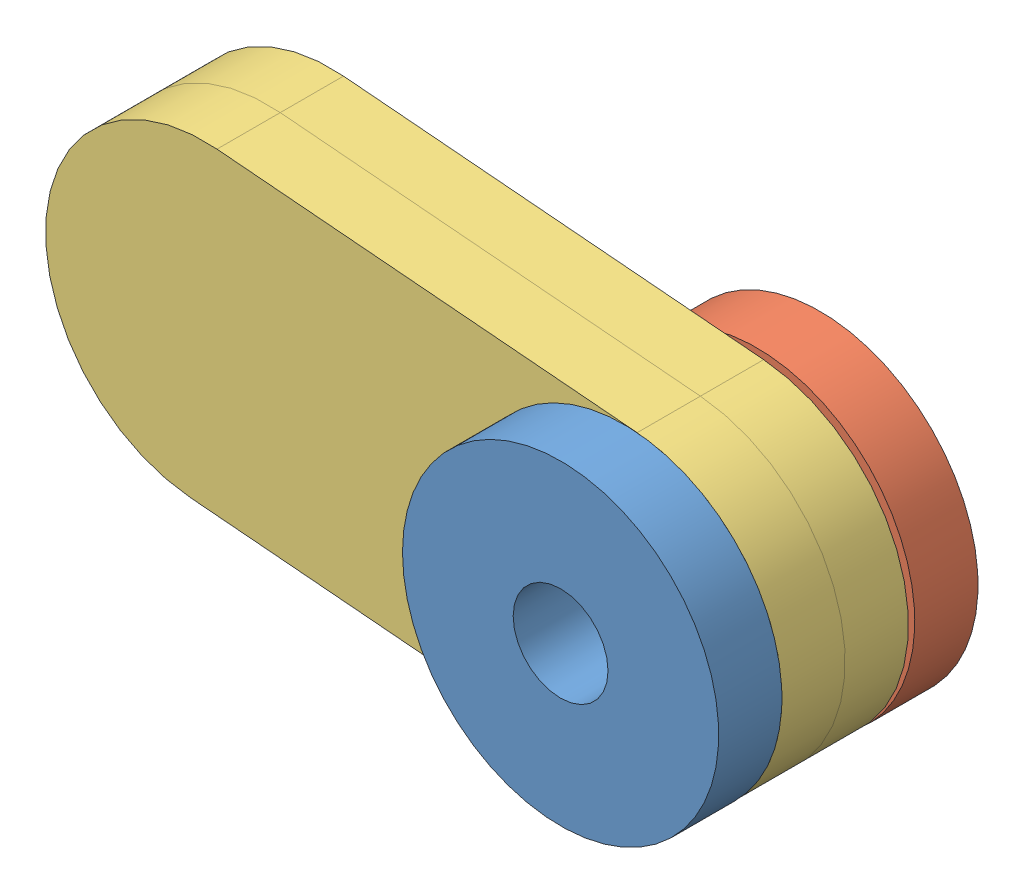
SolidWorks assembly Test Assembly, configuration Default. Lengths in mm.
Overall size (36.14 17.89 12.3).
4 component instances, 3 part files, 6 mates.
Components (placement in the parent):
- 15 O Pin 6mm-1: 15 O Pin 6mm [Default] at (6.8594 6.8797 9.9929) size (15 15 9.3)
- 15 O washer -1: 15 O washer  [Default] at (6.8594 6.8797 3.8429) x (0.999923 0.012409 0) z (0 0 1) size (15 15 3)
- Test Link-1: Test Link [Default] at (-3.1051 7.7213 13.1429) x (0.996452 -0.084166 0) z (0 0 1) size (35 15 3)
- Test Link-2: Test Link [Default] at (-3.1051 7.7213 10.1429) x (0.996452 -0.084166 0) z (0 0 1) size (35 15 3)
Mates (geometry in assembly coordinates):
- Concentric1: concentric anti-aligned: cylinder of 15 O Pin 6mm-1 through (6.8594 6.8797 13.1429) axis (0 0 -1) radius 4.9; cylinder of Test Link-1 through (6.8594 6.8797 10.1429) axis (0 0 1) radius 5
- Coincident1: coincident anti-aligned: plane of 15 O Pin 6mm-1 through (6.8594 6.8797 13.1429) normal (0 0 -1); plane of Test Link-1 through (-13.0696 8.563 13.1429) normal (0 0 1)
- Concentric2: concentric: cylinder of 15 O Pin 6mm-1 through (6.8594 6.8797 13.1429) axis (0 0 -1) radius 2.25; cylinder of 15 O washer -1 through (6.8594 6.8797 -4.8477) axis (0 0 -1) radius 2.25
- Coincident2: coincident anti-aligned: plane of 15 O Pin 6mm-1 through (6.8594 6.8797 6.8429) normal (0 0 -1); plane of 15 O washer -1 through (6.8594 6.8797 6.8429) normal (0 0 1)
- Concentric3: concentric anti-aligned: cylinder of 15 O Pin 6mm-1 through (6.8594 6.8797 13.1429) axis (0 0 -1) radius 4.9; cylinder of Test Link-2 through (6.8594 6.8797 3.8429) axis (0 0 1) radius 5
- Coincident3: coincident anti-aligned: plane of Test Link-1 through (-13.0696 8.563 10.1429) normal (0 0 -1); plane of Test Link-2 through (-13.0696 8.563 10.1429) normal (0 0 1)
